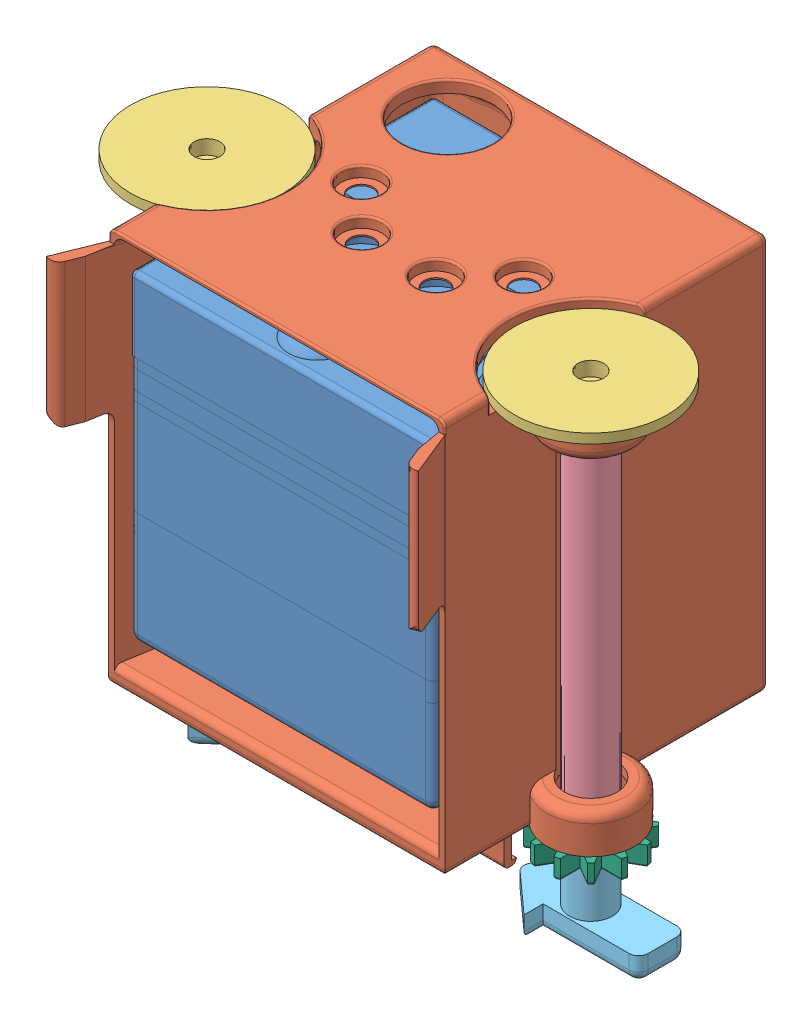
SolidWorks assembly 2DoF_Shell, configuration Default. Lengths in mm.
Overall size (56.2 51.4 38.75).
11 component instances, 7 part files, 20 mates.
Components (placement in the parent):
- servoShell-3: servoShell [Default] at (21.2364 20.5926 29.3924) x (1 0 0) z (0 -1 0) size (31.8 32.3 38.65)
- Part7^2DoF_Shell-1: Part7^2DoF_Shell [Default] at origin size (52.8 47.4 38.75) (virtual)
- Part10^2DoF_Shell-1: Part10^2DoF_Shell [Default] at (0 35.7405 0) x (1 0 0) z (0 1 0) size (16 16 8.3) (virtual)
- Part11^2DoF_Shell-1: Part11^2DoF_Shell [Default] at (0 30.8905 0) x (-1 0 0) z (0 -1 0) size (4.5 4.5 42.55) (virtual)
- arrow^2DoF_Shell-1: arrow^2DoF_Shell [Default] at (0 -11.6595 0) x (-1 0 0) z (0 -1 0) size (14.51 9 8.75) (virtual)
- locking gear^2DoF_Shell-1: locking gear^2DoF_Shell [Default] at (0 -5.6595 0) x (-1 0 0) z (0 -1 0) size (9.81 9.81 2.28) (virtual)
- locking_pin^2DoF_Shell-1: locking_pin^2DoF_Shell [Default] at (0 -3.6595 0) x (1 0 0) z (0 1 0) size (33.01 7.1 6.5) (virtual)
- locking gear^2DoF_Shell-2: locking gear^2DoF_Shell [Default] at (40.2 -5.6595 0) x (-1 0 0) z (0 -1 0) size (9.81 9.81 2.28) (virtual)
- Part11^2DoF_Shell-2: Part11^2DoF_Shell [Default] at (40.2 30.8905 0) x (-1 0 0) z (0 -1 0) size (4.5 4.5 42.55) (virtual)
- Part10^2DoF_Shell-2: Part10^2DoF_Shell [Default] at (40.2 35.7405 0) x (1 0 0) z (0 1 0) size (16 16 8.3) (virtual)
- arrow^2DoF_Shell-2: arrow^2DoF_Shell [Default] at (4.2953 -11.6595 86.7932) x (1 0 0) z (0 -1 0) size (14.51 9 8.75) (virtual)
Mates (geometry in assembly coordinates):
- InPlace1: in place: plane of Part7^2DoF_Shell-1 through (0 34.9905 0) normal (0 1 0); plane of ? through (0 34.9905 0) normal (0 1 0); moOrthogonalPlaneRef_w of Part7^2DoF_Shell-1 through (0 34.9905 0) normal (0 1 0); plane of ? through (0 34.9905 0) normal (0 0 -1); plane of Part7^2DoF_Shell-1 through (0 34.9905 0) normal (0 1 0); plane of ? through (0 34.9905 0) normal (1 0 0); plane of Part7^2DoF_Shell-1 through (0 35.7405 0) normal (0 1 0); unknown of Part10^2DoF_Shell-1
- Coincident2: coincident: plane of Part7^2DoF_Shell-1; plane of Part10^2DoF_Shell-1
- Coincident3: coincident: moOrthogonalPlaneRef_w of Part7^2DoF_Shell-1 through (0 35.7405 0) normal (0 0 -1); plane of Part10^2DoF_Shell-1 through (0 35.7405 0) normal (0 0 -1)
- Coincident4: coincident: moOrthogonalPlaneRef_w of Part7^2DoF_Shell-1 through (0 35.7405 0) normal (-1 0 0); plane of Part10^2DoF_Shell-1 through (0 35.7405 0) normal (1 0 0)
- InPlace2: in place: plane of ? through (-17.9524 32.4905 43.3966) normal (0 -1 0); plane of ? through (0 32.4905 0) normal (0 -1 0); plane of ? through (-17.9524 32.4905 43.3966) normal (0 -1 0); plane of ? through (0 32.4905 0) normal (0 0 -1); plane of ? through (-17.9524 32.4905 43.3966) normal (0 -1 0); plane of ? through (0 32.4905 0) normal (-1 0 0); plane of Part10^2DoF_Shell-1 through (-17.9524 30.8905 43.3966) normal (0 -1 0); unknown of Part11^2DoF_Shell-1
- Coincident5: coincident: plane of Part10^2DoF_Shell-1; plane of Part11^2DoF_Shell-1
- Coincident6: coincident: moOrthogonalPlaneRef_w of Part10^2DoF_Shell-1 through (0 30.8905 0) normal (0 0 -1); plane of Part11^2DoF_Shell-1 through (0 30.8905 0) normal (0 0 -1)
- Coincident7: coincident: moOrthogonalPlaneRef_w of Part10^2DoF_Shell-1 through (0 30.8905 0) normal (1 0 0); plane of Part11^2DoF_Shell-1 through (0 30.8905 0) normal (-1 0 0)
- InPlace3: in place: plane of ? through (0 -7.6595 0) normal (0 -1 0); plane of ? through (0 -7.6595 0) normal (0 -1 0); plane of ? through (0 -7.6595 0) normal (0 -1 0); plane of ? through (0 -7.6595 0) normal (0 0 -1); plane of ? through (0 -7.6595 0) normal (0 -1 0); plane of ? through (0 -7.6595 0) normal (-1 0 0); plane of Part11^2DoF_Shell-1 through (0 -11.6595 0) normal (0 -1 0); unknown of arrow^2DoF_Shell-1
- Coincident1: coincident: plane of Part11^2DoF_Shell-1; plane of arrow^2DoF_Shell-1
- Coincident2: coincident: moOrthogonalPlaneRef_w of Part11^2DoF_Shell-1 through (0 -11.6595 0) normal (0 0 -1); plane of arrow^2DoF_Shell-1 through (0 -11.6595 0) normal (0 0 -1)
- Coincident3: coincident: moOrthogonalPlaneRef_w of Part11^2DoF_Shell-1 through (0 -11.6595 0) normal (1 0 0); plane of arrow^2DoF_Shell-1 through (0 -11.6595 0) normal (-1 0 0)
- InPlace4: in place: plane of ? through (0 -5.1595 0) normal (0 -1 0); plane of ? through (0 -5.1595 0) normal (0 -1 0); plane of ? through (0 -5.1595 0) normal (0 -1 0); plane of ? through (0 -5.1595 0) normal (0 0 -1); plane of ? through (0 -5.1595 0) normal (0 -1 0); plane of ? through (0 -5.1595 0) normal (-1 0 0); plane of Part11^2DoF_Shell-1 through (0 -5.6595 0) normal (0 -1 0); unknown of locking gear^2DoF_Shell-1
- Coincident1: coincident: plane of Part11^2DoF_Shell-1; plane of locking gear^2DoF_Shell-1
- Coincident2: coincident: moOrthogonalPlaneRef_w of Part11^2DoF_Shell-1 through (0 -5.6595 0) normal (0 0 -1); plane of locking gear^2DoF_Shell-1 through (0 -5.6595 0) normal (0 0 -1)
- Coincident3: coincident: moOrthogonalPlaneRef_w of Part11^2DoF_Shell-1 through (0 -5.6595 0) normal (1 0 0); plane of locking gear^2DoF_Shell-1 through (0 -5.6595 0) normal (-1 0 0)
- InPlace5: in place: plane of Part7^2DoF_Shell-1 through (0 -3.6595 0) normal (0 1 0); plane of locking_pin^2DoF_Shell-1 through (0 -3.6595 0) normal (0 1 0); plane of Part7^2DoF_Shell-1 through (0 -3.6595 0) normal (0 1 0); plane of locking_pin^2DoF_Shell-1 through (0 -3.6595 0) normal (0 0 -1); plane of Part7^2DoF_Shell-1 through (0 -3.6595 0) normal (0 1 0); plane of locking_pin^2DoF_Shell-1 through (0 -3.6595 0) normal (1 0 0); plane of Part7^2DoF_Shell-1 through (0 -3.6595 0) normal (0 1 0); unknown of locking_pin^2DoF_Shell-1
- Coincident4: coincident: plane of Part7^2DoF_Shell-1; plane of locking_pin^2DoF_Shell-1
- Coincident5: coincident: moOrthogonalPlaneRef_w of Part7^2DoF_Shell-1 through (0 -3.6595 0) normal (0 0 -1); plane of locking_pin^2DoF_Shell-1 through (0 -3.6595 0) normal (0 0 -1)
- Coincident6: coincident: moOrthogonalPlaneRef_w of Part7^2DoF_Shell-1 through (0 -3.6595 0) normal (-1 0 0); plane of locking_pin^2DoF_Shell-1 through (0 -3.6595 0) normal (1 0 0)
